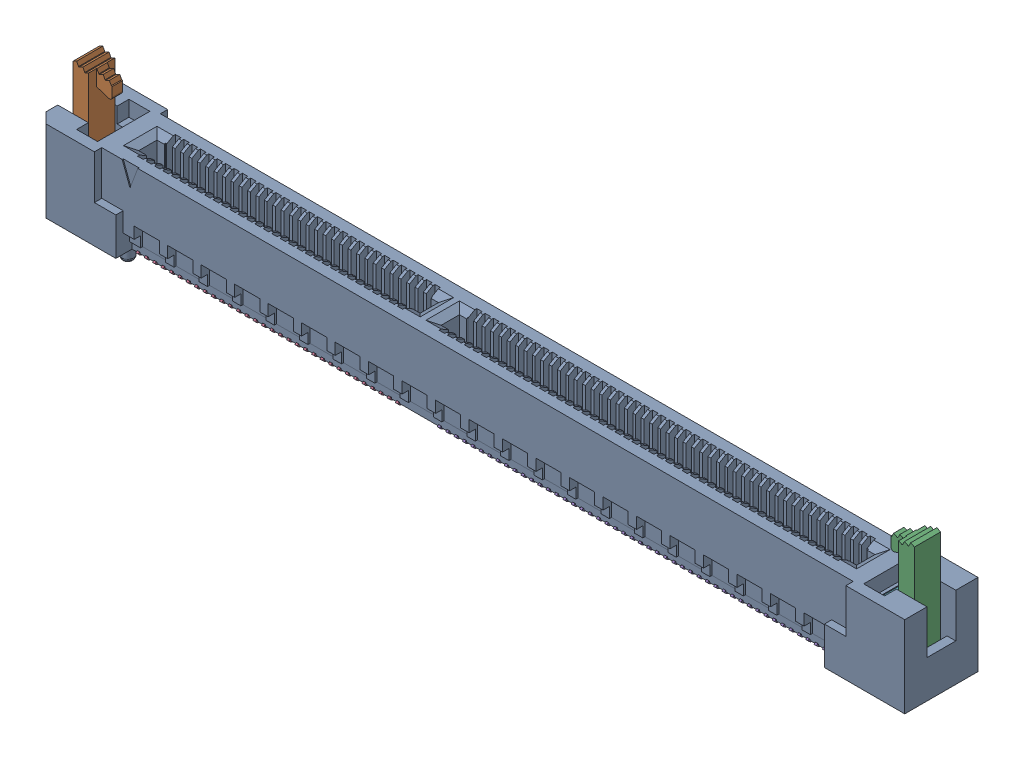
SolidWorks assembly HSEC8_180_01_S_DV_A_BL, configuration Default. Lengths in mm.
Overall size (83.05 13.7 7).
7 component instances, 5 part files, 0 mates.
Components (placement in the parent):
- _HSEC8_180_01_S_DV_A_BLter_2-1: _HSEC8_180_01_S_DV_A_BLter_2 [Default] at origin size (83.05 9.3 7)
- _LTC_04_4-1: _LTC_04_4 [Default] at (-39.45 1.75 0) size (3.4 11.6 2.75)
- _LTC_04_4-2: _LTC_04_4 [Default] at (39.45 1.75 0) x (-1 0 0) z (0 0 -1) size (3.4 11.6 2.75)
- _C_188_02_Pin_32_01_7-1: _C_188_02_Pin_32_01_7 [Default] at (-33.2 -0.183 0) x (0 0 1) z (-1 0 0) size (4.26 5.75 25.38)
- _C_188_02_Pin_48_01_9-1: _C_188_02_Pin_48_01_9 [Default] at (-4.4 -0.183 0) x (0 0 1) z (-1 0 0) size (4.26 5.75 38.18)
- _WT_25_02_T_Latching_Option_BL_11-1: _WT_25_02_T_Latching_Option_BL_11 [Default] at (-37.05 6.245 0) x (0 0 -1) z (1 0 0) size (4.45 7.73 0.25)
- _WT_25_02_T_Latching_Option_BL_11-2: _WT_25_02_T_Latching_Option_BL_11 [Default] at (37.05 6.245 0) x (0 0 -1) z (1 0 0) size (4.45 7.73 0.25)
